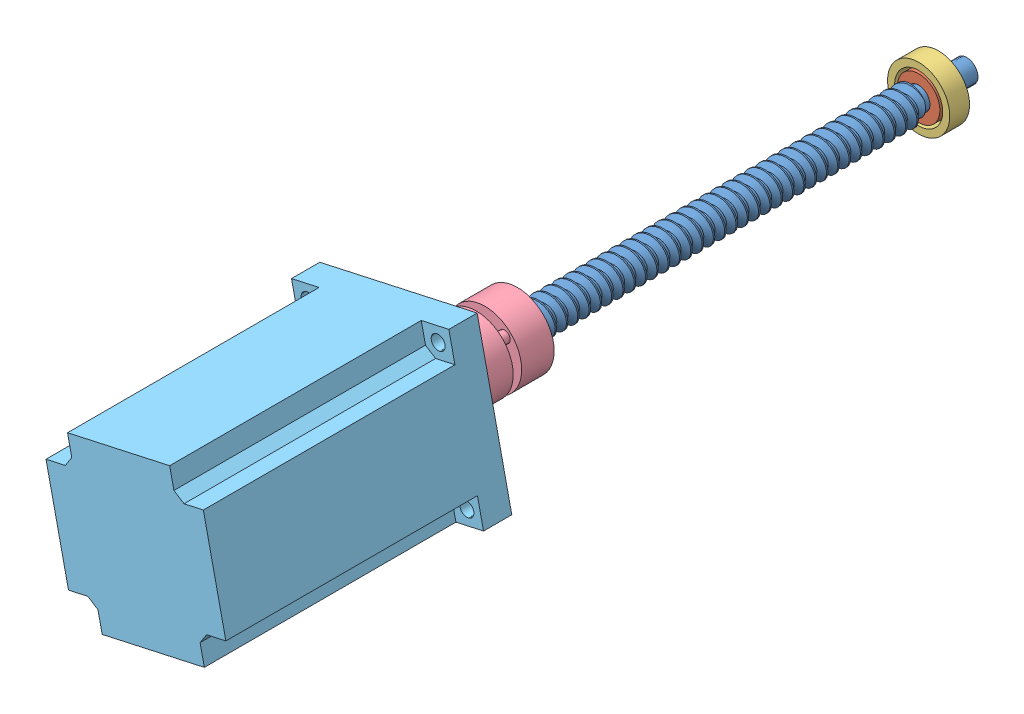
SolidWorks assembly Z drive_1, configuration Default. Lengths in mm.
Overall size (67.93 67.93 293.9).
8 component instances, 6 part files, 6 mates.
Components (placement in the parent):
- Z screw-1: Z screw [Default] at (29.3541 63.3718 -160.288) x (0 0 1) z (0.556143 -0.831086 0) size (170 12.29 12.02)
- 608 bearing-1: 608 bearing [Default] at (23.3505 62.3336 -247.8153) x (-0.639932 -0.768431 0) z (0 0 1) size (22 22 7) (flexible)
  - inner race-1: inner race [Default] at (-10.3949 5.6455 9.7773) x (0.96347 0.267816 0) z (0 0 1) size (15 15 7)
  - outer race-1: outer race [Default] at (-10.3949 5.6455 9.7773) size (22 22 7)
- coupling WQ-C26L26-1: coupling WQ-C26L26 [Default] at (34.3406 66.7087 -74.588) x (-0.69602 -0.718022 0) z (0 0 1) size (26 26 26)
- 57 stepper motor-1: 57 stepper motor [Default] at (95.0219 58.1833 -86.841) x (-0.215229 0.976564 0) z (0 0 1) size (57 57 120) (flexible)
  - motor body-1: motor body [Default] at (21.3859 57.4242 33.703) size (57 57 100.6)
  - motor axis-1: motor axis [Default] at (21.3859 57.4242 33.703) x (0.824601 0.565715 0) z (0 0 -1) size (8 8 21)
Mates (geometry in assembly coordinates):
- Concentric1: concentric anti-aligned: cylinder of Z screw-1 through (34.3406 66.7087 -78.038) axis (0 0 1) radius 4; cylinder of 608 bearing-1/inner race-1 through (34.3406 66.7087 -231.038) axis (0 0 -1) radius 4
- Distance1: distance = 10 mm aligned: plane of Z screw-1 through (29.3541 63.3718 -248.038) normal (0 0 -1); plane of 608 bearing-1/inner race-1 through (34.3406 66.7087 -238.038) normal (0 0 -1)
- Concentric2: concentric aligned: cylinder of Z screw-1 through (34.3406 66.7087 -78.038) axis (0 0 1) radius 4; cylinder of coupling WQ-C26L26-1 through (34.3406 66.7087 -89.088) axis (0 0 1) radius 4
- Concentric3: concentric anti-aligned: cylinder of coupling WQ-C26L26-1 through (34.3406 66.7087 -63.088) axis (0 0 -1) radius 4; cylinder of 57 stepper motor-1/motor axis-1 through (34.3406 66.7087 -74.138) axis (0 0 1) radius 4
- Distance2: distance = 0.45 mm aligned: plane of coupling WQ-C26L26-1 through (34.3406 66.7087 -74.588) normal (0 0 -1); plane of 57 stepper motor-1/motor axis-1 through (34.3406 66.7087 -74.138) normal (0 0 -1)
- Distance3: distance = 0.45 mm aligned: plane of Z screw-1 through (29.3541 63.3718 -78.038) normal (0 0 1); plane of coupling WQ-C26L26-1 through (34.3406 66.7087 -77.588) normal (0 0 1)
